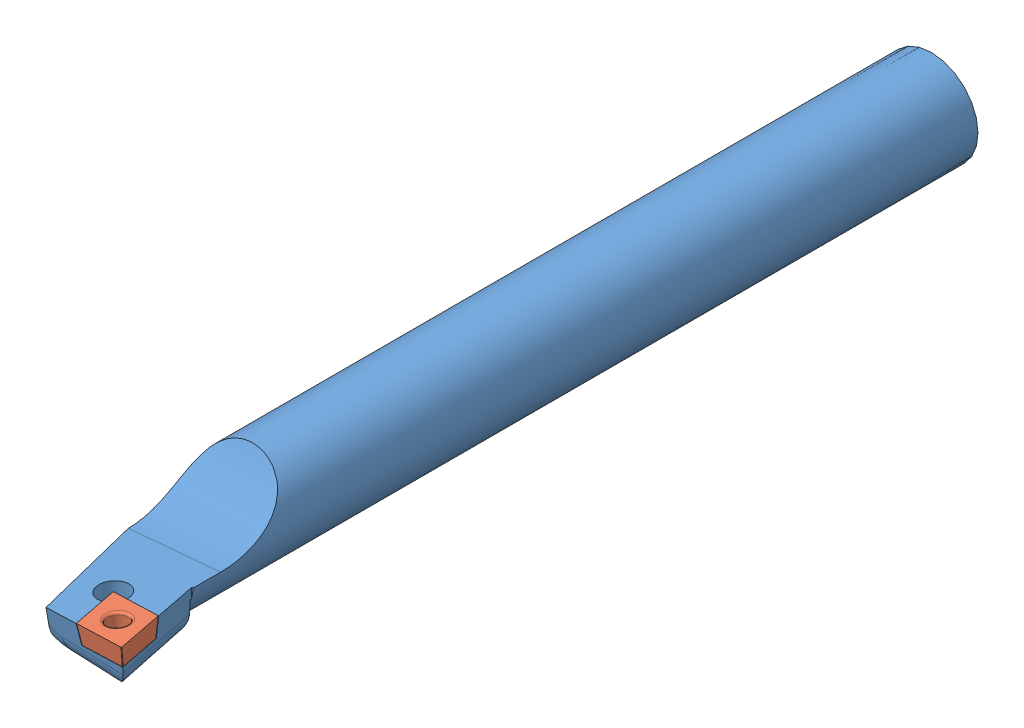
SolidWorks assembly seucr assem, configuration Default. Lengths in mm.
Overall size (65.75 24.32 158.4).
2 component instances, 2 part files, 3 mates.
Components (placement in the parent):
- SEUCR16-1: SEUCR16 [Default] at origin size (65.75 28.03 158.4)
- ECMT insert-2: ECMT insert [Default] at (6.1505 -2.0203 70.7235) x (0.646977 0.056603 -0.760406) z (0.757512 0.066274 0.649448) size (9.97 3.18 12.94)
Mates (geometry in assembly coordinates):
- Coincident1: coincident anti-aligned: plane of SEUCR16-1 through (0.3607 -4.123 0) normal (-0.087156 0.996195 0); plane of ECMT insert-2 through (6.2891 -3.6043 70.7235) normal (0.087156 -0.996195 0)
- Coincident2: coincident anti-aligned: plane of SEUCR16-1 through (-12.441 -2.0508 2.6723) normal (0.956541 0.206021 -0.206362); plane of ECMT insert-2 through (1.0719 -0.8686 66.4882) normal (-0.956541 -0.206021 0.206362)
- Coincident7: coincident anti-aligned: plane of SEUCR16-1 through (-3.3755 -1.2577 66.2542) normal (-0.06237 0.116878 0.991186); plane of ECMT insert-2 through (9.2495 -0.1532 66.9184) normal (0.06237 -0.116878 -0.991186)
